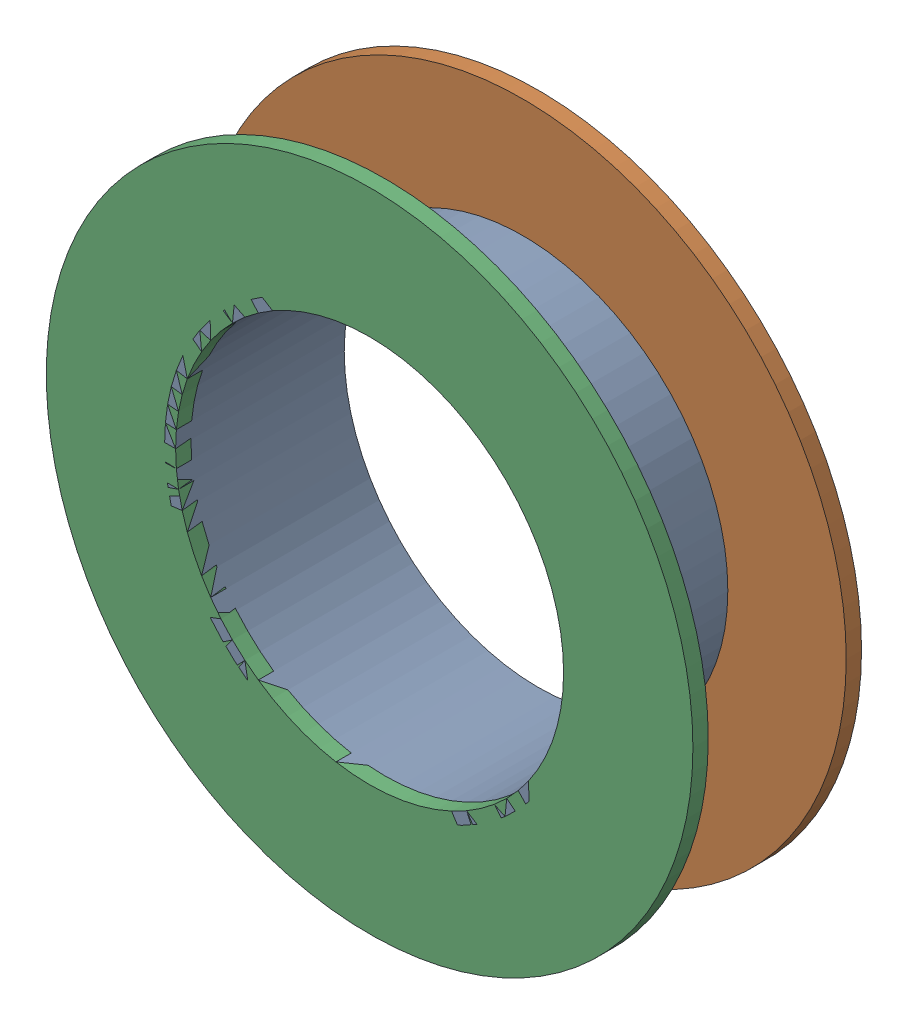
SolidWorks assembly Pad SWD-4(20.574mm,48.387mm) on Multi-Layer, configuration Predeterminado. Lengths in mm.
Overall size (1.5 1.5 0.39).
6 component instances, 2 part files, 0 mates.
Components (placement in the parent):
- Pad Hole-1-1: Pad Hole-1 [Predeterminado] at (20.574 48.387 -0.4013) size (0.95 0.95 0.39)
  - Pad Hole-Part-1-1-1: Pad Hole-Part-1-1 [Predeterminado] at origin size (0.95 0.95 0.39)
- Top Layer-1-1: Top Layer-1 [Predeterminado] at (20.574 48.387 -0.4013) size (1.5 1.5 0.04)
  - Top Layer-Part-1-1-1: Top Layer-Part-1-1 [Predeterminado] at origin size (1.5 1.5 0.04)
- Top Layer-1-2: Top Layer-1 [Predeterminado] at (20.574 48.387 -0.0457) size (1.5 1.5 0.04)
  - Top Layer-Part-1-1-1: Top Layer-Part-1-1 [Predeterminado] at origin size (1.5 1.5 0.04)
